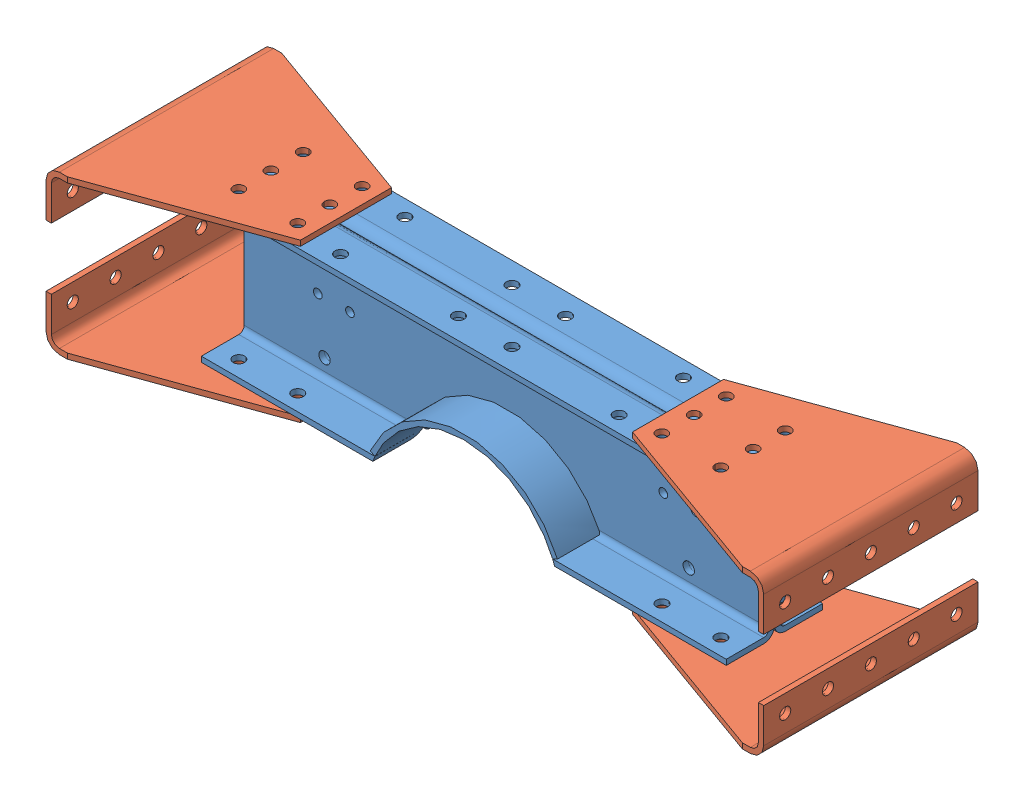
SolidWorks assembly SUB-1700-075, configuration Collapsed - No fasteners. Lengths in mm.
Overall size (850.9 187.32 254).
38 component instances, 4 part files, 114 mates.
Components (placement in the parent):
- 2526-CC2-1: 2526-CC2 [2526-CC2-001] x (-1 0 0) z (0 0 -1)
- 2526-CC2-2: 2526-CC2 [2526-CC2-001] at origin
- 2518-CC2-1: 2518-CC2 [2518-CC2-001] at (-425.45 93.6625 0)
- 2518-CC2-4: 2518-CC2 [2518-CC2-001] at (-425.45 -93.6625 0) x (1 0 0) z (0 0 -1)
- 2518-CC2-2: 2518-CC2 [2518-CC2-001] at (425.45 93.6625 0) x (-1 0 0) z (0 0 -1)
- 2518-CC2-3: 2518-CC2 [2518-CC2-001] at (425.45 -93.6625 0) x (-1 0 0) z (0 0 1)
- 08130XXXFH8Y-16: 08130XXXFH8Y [08130125FH8Y] at (-215.9 -93.6625 38.1) x (0.866025 0 0.5) z (0 -1 0) (suppressed, hidden)
- 08130XXXFH8Y-1: 08130XXXFH8Y [08130125FH8Y] at (215.9 93.6625 38.1) x (0.866025 0 -0.5) z (0 1 0) (suppressed, hidden)
- 08130XXXFH8Y-5: 08130XXXFH8Y [08130125FH8Y] at (215.9 -93.6625 38.1) x (0.866025 0 0.5) z (0 -1 0) (suppressed, hidden)
- 08130XXXFH8Y-3: 08130XXXFH8Y [08130125FH8Y] at (-215.9 93.6625 38.1) x (0 0 -1) z (0 1 0) (suppressed, hidden)
- 08130XXXFH8Y-15: 08130XXXFH8Y [08130125FH8Y] at (-285.75 -93.6625 38.1) x (0.866025 0 0.5) z (0 -1 0) (suppressed, hidden)
- 08130XXXFH8Y-2: 08130XXXFH8Y [08130125FH8Y] at (-285.75 93.6625 38.1) x (0 0 -1) z (0 1 0) (suppressed, hidden)
- 08130XXXFH8Y-14: 08130XXXFH8Y [08130125FH8Y] at (285.75 93.6625 38.1) x (0.866025 0 -0.5) z (0 1 0) (suppressed, hidden)
- 08130XXXFH8Y-4: 08130XXXFH8Y [08130125FH8Y] at (285.75 -93.6625 38.1) x (0.866025 0 0.5) z (0 -1 0) (suppressed, hidden)
- XXXXFLN8Y-14: XXXXFLN8Y [0813FLN8Y] at (-285.75 -80.9625 38.1) x (0 0 1) z (0 1 0) (suppressed, hidden)
- XXXXFLN8Y-2: XXXXFLN8Y [0813FLN8Y] at (-215.9 80.9625 38.1) x (0 0 -1) z (0 -1 0) (suppressed, hidden)
- XXXXFLN8Y-3: XXXXFLN8Y [0813FLN8Y] at (-285.75 80.9625 38.1) x (0.866025 0 0.5) z (0 -1 0) (suppressed, hidden)
- XXXXFLN8Y-13: XXXXFLN8Y [0813FLN8Y] at (-215.9 -80.9625 38.1) x (0 0 1) z (0 1 0) (suppressed, hidden)
- XXXXFLN8Y-4: XXXXFLN8Y [0813FLN8Y] at (215.9 80.9625 38.1) x (0.866025 0 0.5) z (0 -1 0) (suppressed, hidden)
- XXXXFLN8Y-15: XXXXFLN8Y [0813FLN8Y] at (215.9 -80.9625 38.1) x (0.866025 0 0.5) z (0 1 0) (suppressed, hidden)
- XXXXFLN8Y-1: XXXXFLN8Y [0813FLN8Y] at (285.75 80.9625 38.1) x (0.866025 0 0.5) z (0 -1 0) (suppressed, hidden)
- XXXXFLN8Y-16: XXXXFLN8Y [0813FLN8Y] at (285.75 -80.9625 38.1) x (0.866025 0 0.5) z (0 1 0) (suppressed, hidden)
- 08130XXXFH8Y-7: 08130XXXFH8Y [08130125FH8Y] at (215.9 93.6625 -38.1) x (0.866025 0 -0.5) z (0 1 0) (suppressed, hidden)
- XXXXFLN8Y-6: XXXXFLN8Y [0813FLN8Y] at (215.9 80.9625 -38.1) x (0.866025 0 0.5) z (0 -1 0) (suppressed, hidden)
- 08130XXXFH8Y-6: 08130XXXFH8Y [08130125FH8Y] at (285.75 93.6625 -38.1) x (0.866025 0 -0.5) z (0 1 0) (suppressed, hidden)
- XXXXFLN8Y-5: XXXXFLN8Y [0813FLN8Y] at (285.75 80.9625 -38.1) x (0.866025 0 0.5) z (0 -1 0) (suppressed, hidden)
- 08130XXXFH8Y-9: 08130XXXFH8Y [08130125FH8Y] at (-215.9 93.6625 -38.1) x (0 0 -1) z (0 1 0) (suppressed, hidden)
- 08130XXXFH8Y-8: 08130XXXFH8Y [08130125FH8Y] at (-285.75 93.6625 -38.1) x (0 0 -1) z (0 1 0) (suppressed, hidden)
- XXXXFLN8Y-8: XXXXFLN8Y [0813FLN8Y] at (-285.75 80.9625 -38.1) x (0.866025 0 0.5) z (0 -1 0) (suppressed, hidden)
- XXXXFLN8Y-7: XXXXFLN8Y [0813FLN8Y] at (-215.9 80.9625 -38.1) x (0 0 -1) z (0 -1 0) (suppressed, hidden)
- 08130XXXFH8Y-11: 08130XXXFH8Y [08130125FH8Y] at (-285.75 -93.6625 -38.1) x (0.866025 0 0.5) z (0 -1 0) (suppressed, hidden)
- 08130XXXFH8Y-10: 08130XXXFH8Y [08130125FH8Y] at (-215.9 -93.6625 -38.1) x (0.866025 0 0.5) z (0 -1 0) (suppressed, hidden)
- 08130XXXFH8Y-13: 08130XXXFH8Y [08130125FH8Y] at (215.9 -93.6625 -38.1) x (0.866025 0 0.5) z (0 -1 0) (suppressed, hidden)
- 08130XXXFH8Y-12: 08130XXXFH8Y [08130125FH8Y] at (285.75 -93.6625 -38.1) x (0.866025 0 0.5) z (0 -1 0) (suppressed, hidden)
- XXXXFLN8Y-10: XXXXFLN8Y [0813FLN8Y] at (-285.75 -80.9625 -38.1) x (0 0 1) z (0 1 0) (suppressed, hidden)
- XXXXFLN8Y-9: XXXXFLN8Y [0813FLN8Y] at (-215.9 -80.9625 -38.1) x (0 0 1) z (0 1 0) (suppressed, hidden)
- XXXXFLN8Y-12: XXXXFLN8Y [0813FLN8Y] at (215.9 -80.9625 -38.1) x (0.866025 0 0.5) z (0 1 0) (suppressed, hidden)
- XXXXFLN8Y-11: XXXXFLN8Y [0813FLN8Y] at (285.75 -80.9625 -38.1) x (0.866025 0 0.5) z (0 1 0) (suppressed, hidden)
Mates (geometry in assembly coordinates):
- Coincident119: coincident anti-aligned: plane of ?; plane of assembly
- Coincident53: coincident anti-aligned: plane of ?; plane of assembly
- Coincident78: coincident aligned: plane of ?; plane of assembly
- Coincident96: coincident aligned: plane of ?; plane of assembly
- Distance2: distance = 93.6625 mm aligned: plane of ?; plane of assembly
- Distance3: distance = 425.45 mm aligned: plane of ?; plane of assembly
- Coincident97: coincident anti-aligned: plane of ?; plane of assembly
- Distance4: distance = 425.45 mm aligned: plane of ?; plane of assembly
- Distance5: distance = 93.6625 mm anti-aligned: plane of ?; plane of assembly
- Coincident98: coincident anti-aligned: plane of ?; plane of assembly
- Distance6: distance = 425.45 mm anti-aligned: plane of ?; plane of assembly
- Distance7: distance = 93.6625 mm aligned: plane of ?; plane of assembly
- Coincident99: coincident aligned: plane of ?; plane of assembly
- Distance8: distance = 425.45 mm anti-aligned: plane of ?; plane of assembly
- Distance9: distance = 93.6625 mm anti-aligned: plane of ?; plane of assembly
- Coincident116: coincident aligned: plane of ?; plane of assembly
- Coincident117: coincident aligned: plane of ?; plane of assembly
- Coincident118: coincident aligned: plane of ?; plane of assembly
- Concentric1: concentric anti-aligned: cylinder of ?; cylinder of ?
- Coincident120: coincident anti-aligned: plane of ?; plane of ?
- Concentric2: concentric anti-aligned: circle of ?; cylinder of ?
- Coincident121: coincident anti-aligned: plane of ?; plane of ?
- Coincident122: coincident anti-aligned: plane of ?; plane of ?
- Coincident123: coincident anti-aligned: plane of ?; plane of ?
- Concentric3: concentric anti-aligned: circle of ?; cylinder of ?
- Concentric4: concentric anti-aligned: circle of ?; cylinder of ?
- Coincident124: coincident anti-aligned: plane of ?; plane of ?
- Concentric5: concentric anti-aligned: circle of ?; cylinder of ?
- Coincident125: coincident anti-aligned: plane of ?; plane of ?
- Concentric6: concentric anti-aligned: circle of ?; cylinder of ?
- Concentric7: concentric anti-aligned: circle of ?; cylinder of ?
- Coincident126: coincident anti-aligned: plane of ?; plane of ?
- Concentric8: concentric anti-aligned: circle of ?; circle of ?
- Coincident127: coincident anti-aligned: plane of ?; plane of ?
- Concentric9: concentric anti-aligned: circle of ?; cylinder of ?
- Coincident128: coincident anti-aligned: plane of ?; plane of ?
- Concentric10: concentric anti-aligned: circle of ?; circle of ?
- Coincident129: coincident anti-aligned: plane of ?; plane of ?
- Coincident130: coincident anti-aligned: plane of ?; plane of ?
- Coincident131: coincident anti-aligned: plane of ?; plane of ?
- Concentric11: concentric anti-aligned: circle of ?; cylinder of ?
- Concentric12: concentric anti-aligned: circle of ?; cylinder of ?
- Coincident132: coincident anti-aligned: plane of ?; plane of ?
- Coincident133: coincident anti-aligned: plane of ?; plane of ?
- Concentric13: concentric anti-aligned: circle of ?; cylinder of ?
- Concentric14: concentric anti-aligned: circle of ?; circle of ?
- Concentric15: concentric anti-aligned: circle of ?; cylinder of ?
- Coincident134: coincident anti-aligned: plane of ?; plane of ?
- Coincident135: coincident anti-aligned: plane of ?; plane of ?
- Concentric16: concentric anti-aligned: circle of ?; cylinder of ?
- Concentric17: concentric anti-aligned: circle of ?; cylinder of ?
- Concentric18: concentric anti-aligned: circle of ?; cylinder of ?
- Coincident137: coincident anti-aligned: plane of ?; plane of ?
- Coincident138: coincident anti-aligned: plane of ?; plane of ?
- Coincident139: coincident anti-aligned: plane of ?; plane of ?
- Concentric19: concentric anti-aligned: circle of ?; circle of ?
- Coincident140: coincident anti-aligned: plane of ?; plane of ?
- Concentric20: concentric anti-aligned: circle of ?; circle of ?
- Concentric21: concentric anti-aligned: circle of ?; cylinder of ?
- Concentric22: concentric anti-aligned: circle of ?; cylinder of ?
- Coincident141: coincident anti-aligned: plane of ?; plane of ?
- Coincident142: coincident anti-aligned: plane of ?; plane of ?
- Concentric23: concentric anti-aligned: circle of ?; cylinder of ?
- Concentric24: concentric anti-aligned: circle of ?; cylinder of ?
- Coincident143: coincident anti-aligned: plane of ?; plane of ?
- Coincident144: coincident anti-aligned: plane of ?; plane of ?
- Concentric25: concentric anti-aligned: circle of ?; cylinder of ?
- Concentric26: concentric anti-aligned: circle of ?; cylinder of ?
- Coincident145: coincident anti-aligned: plane of ?; plane of ?
- Coincident146: coincident anti-aligned: plane of ?; plane of ?
- Concentric27: concentric anti-aligned: circle of ?; circle of ?
- Concentric28: concentric anti-aligned: circle of ?; circle of ?
- Coincident147: coincident anti-aligned: plane of ?; plane of ?
- Coincident148: coincident anti-aligned: plane of ?; plane of ?
- Concentric29: concentric anti-aligned: circle of ?; cylinder of ?
- Concentric30: concentric anti-aligned: circle of ?; cylinder of ?
- Coincident149: coincident anti-aligned: plane of ?; plane of ?
- Coincident150: coincident anti-aligned: plane of ?; plane of ?
- Concentric31: concentric anti-aligned: circle of ?; circle of ?
- Concentric32: concentric anti-aligned: circle of ?; circle of ?
- Coincident151: coincident anti-aligned: plane of ?; plane of ?
- Coincident152: coincident anti-aligned: plane of ?; plane of ?
- Parallel1: parallel: line of ?; plane of assembly
- Parallel2: parallel: line of ?; plane of assembly
- Parallel3: parallel: line of ?; plane of assembly
- Parallel4: parallel: line of ?; plane of assembly
- Parallel5: parallel: line of ?; plane of assembly
- Parallel6: parallel: line of ?; plane of assembly
- Parallel7: parallel: line of ?; plane of assembly
- Parallel8: parallel: line of ?; plane of assembly
- Parallel9: parallel: line of ?; plane of assembly
- Parallel10: parallel: line of ?; plane of assembly
- Parallel11: parallel: line of ?; plane of assembly
- Parallel12: parallel: line of ?; plane of assembly
- Parallel13: parallel: line of ?; plane of assembly
- Parallel14: parallel: line of ?; plane of assembly
- Parallel15: parallel: line of ?; plane of assembly
- Parallel16: parallel: line of ?; plane of assembly
- Parallel17: parallel: line of ?; plane of assembly
- Parallel18: parallel: line of ?; plane of assembly
- Parallel19: parallel: line of ?; plane of assembly
- Parallel20: parallel: line of ?; plane of assembly
- Parallel21: parallel: line of ?; plane of assembly
- Parallel22: parallel: line of ?; plane of assembly
- Parallel23: parallel: line of ?; plane of assembly
- Parallel24: parallel: line of ?; plane of assembly
- Parallel25: parallel: line of ?; plane of assembly
- Parallel26: parallel: line of ?; plane of assembly
- Parallel27: parallel: line of ?; plane of assembly
- Parallel28: parallel: line of ?; plane of assembly
- Parallel29: parallel: line of ?; plane of assembly
- Parallel30: parallel: line of ?; plane of assembly
- Parallel31: parallel: line of ?; plane of assembly
- Parallel32: parallel: 
